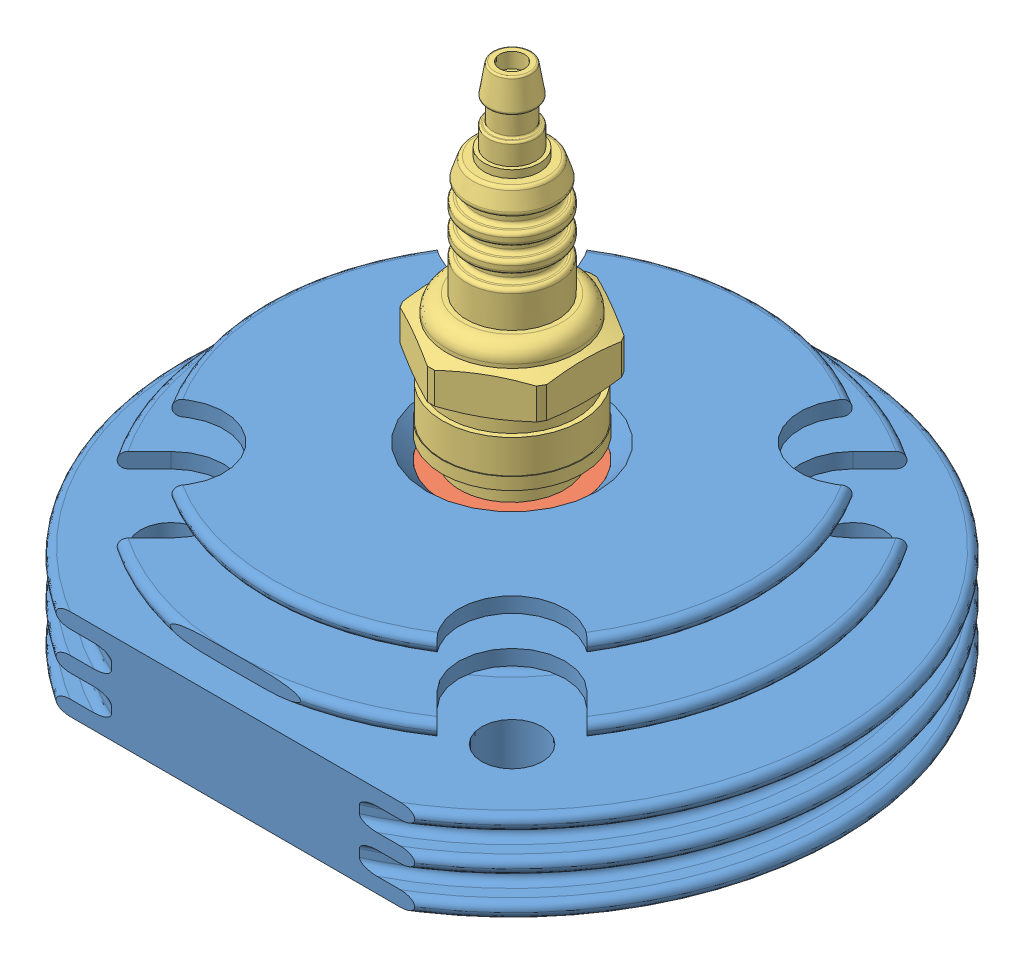
SolidWorks assembly Spark PLug Assembly, configuration Default. Lengths in mm.
Overall size (87 67.69 80).
3 component instances, 3 part files, 4 mates.
Components (placement in the parent):
- Spark Plug Disc-1: Spark Plug Disc [Default] at (44.3893 27.9499 67.7404) size (87 24.25 80)
- Spark plug Screw Cap-1: Spark plug Screw Cap [Default] at (44.3893 27.9499 67.7404) x (0.190448 0 0.981697) z (-0.981697 0 0.190448) size (50 22 50)
- Spark plug-1: Spark plug [Default] at (44.3893 95.4499 67.7404) x (0 -1 0) z (-0.50026 0 0.865875) size (51.5 21.4 19)
Mates (geometry in assembly coordinates):
- Concentric3: concentric: Spark Plug Disc-1, Spark plug Screw Cap-1
- Coincident1: coincident: Spark Plug Disc-1, Spark plug Screw Cap-1
- Concentric4: concentric: Spark plug Screw Cap-1, Spark plug-1
- Coincident2: coincident: Spark plug Screw Cap-1, Spark plug-1
